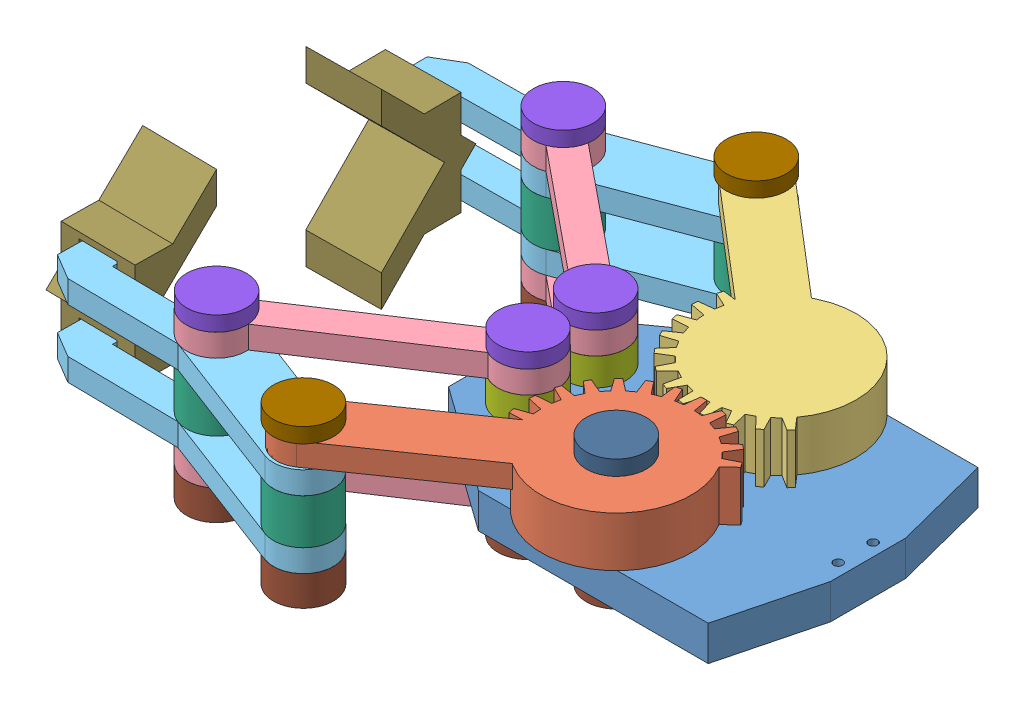
SolidWorks assembly 어셈블리4, configuration 기본. Lengths in mm.
Overall size (177.49 61.17 180).
35 component instances, 12 part files, 78 mates.
Components (placement in the parent):
- base(1)_final-1: base(1)_final [Default] at (138.3176 -17.9209 180) size (117.13 45.17 180)
- gear(2) _M_final-1: gear(2) _M_final [Default] at (28.6998 -14.4209 184.684) x (0.821002 0 -0.570925) z (0.570925 0 0.821002) size (68.4 10 32.98)
- gear_pulley_final-1: gear_pulley_final [Default] at (26.9685 18.9124 176.8375) x (0.760222 0 0.649664) z (0.649664 0 -0.760222) size (68.4 22 32.98)
- arm(4)_final-1: arm(4)_final [Default] at (-36.912 -2.5042 199.1511) x (0.834904 0 -0.550395) z (0.550395 0 0.834904) size (57 4.5 12)
- arm(4)_final-2: arm(4)_final [Default] at (-35.5671 12.4958 159.0173) x (-0.775131 0 -0.631801) z (-0.631801 0 0.775131) size (57 4.5 12)
- lever(4)_final-1: lever(4)_final [Default] at (-64.1108 -7.0042 202.4698) x (-0.934782 0 -0.355221) z (0.355221 0 -0.934782) size (66 4.5 19.65)
- lever(4)_final-2: lever(4)_final [Default] at (-61.4597 7.9958 153.8309) x (-0.936293 0 0.35122) z (0.35122 0 0.936293) size (66 4.5 19.65)
- ring_connect(4)_9mm_final-1: ring_connect(4)_9mm_final [기본] at (-55.6973 -10.7542 211.535) x (0.983529 0 0.180751) z (-0.180751 0 0.983529) size (12 9 12)
- ring_connect(4)_9mm_final-2: ring_connect(4)_9mm_final [기본] at (-53.0075 -10.7542 144.8017) size (12 9 12)
- ring_connect_6mm용(4)_5.5mm_final-1: ring_connect_6mm용(4)_5.5mm_final [기본] at (-18.1267 2.7458 173.2328) x (0.837169 0 0.546944) z (0.546944 0 -0.837169) size (12 5.5 12)
- ring_connect_6mm용(4)_5.5mm_final-2: ring_connect_6mm용(4)_5.5mm_final [기본] at (-18.1267 2.7458 186.7672) x (0.837169 0 0.546944) z (0.546944 0 -0.837169) size (12 5.5 12)
- lever(4)_final-3: lever(4)_final [Default] at (-64.1108 -20.5042 202.4698) x (-0.934782 0 -0.355221) z (0.355221 0 -0.934782) size (66 4.5 19.65)
- lever(4)_final-4: lever(4)_final [Default] at (-61.4597 -5.5042 153.8309) x (-0.936293 0 0.35122) z (0.35122 0 0.936293) size (66 4.5 19.65)
- ring_connect(4)_9mm_final-3: ring_connect(4)_9mm_final [기본] at (-27.6539 -10.7542 222.1916) x (0.987416 0 -0.158147) z (0.158147 0 0.987416) size (12 9 12)
- ring_connect(4)_9mm_final-4: ring_connect(4)_9mm_final [기본] at (-24.9187 -10.7542 134.2651) size (12 9 12)
- ring_connect_6mm용(4)_5.5mm_final-3: ring_connect_6mm용(4)_5.5mm_final [기본] at (-18.1267 -15.2542 186.7672) size (12 5.5 12)
- ring_connect_6mm용(4)_5.5mm_final-4: ring_connect_6mm용(4)_5.5mm_final [기본] at (-18.1267 -15.2542 173.2328) size (12 5.5 12)
- arm(4)_final-3: arm(4)_final [Default] at (-36.912 -25.0042 199.1511) x (0.834904 0 -0.550395) z (0.550395 0 0.834904) size (57 4.5 12)
- arm(4)_final-4: arm(4)_final [Default] at (-35.5671 -25.0042 159.0173) x (0.775131 0 0.631801) z (-0.631801 0 0.775131) size (57 4.5 12)
- link_5.5(4)(2)_30mm_final-1: link_5.5(4)(2)_30mm_final [Default] at (-55.6973 -51.2542 211.535) size (12 33 12)
- link_5.5(4)(2)_30mm_final-2: link_5.5(4)(2)_30mm_final [Default] at (-53.0075 -51.2542 144.8017) size (12 33 12)
- link2_5.5(2)_25.5mm_final-1: link2_5.5(2)_25.5mm_final [Default] at (-27.6539 -48.0042 222.1916) size (12 28.5 12)
- link2_5.5(2)_25.5mm_final-2: link2_5.5(2)_25.5mm_final [Default] at (-24.9187 -48.0042 134.2651) size (12 28.5 12)
- link_5.5(4)(2)_30mm_final-3: link_5.5(4)(2)_30mm_final [Default] at (-18.1267 -51.2542 186.7672) size (12 33 12)
- link_5.5(4)(2)_30mm_final-4: link_5.5(4)(2)_30mm_final [Default] at (-18.1267 -51.2542 173.2328) size (12 33 12)
- link3_5.5_gripper_gear_fianl-1: link3_5.5_gripper_gear_fianl [Default] at (9.2912 -36.0876 196.5) size (12 23 12)
- ring_5.5mm_final-3: ring_5.5mm_final [기본] at (-27.6539 -15.2542 222.1916) x (-0.837169 0 -0.546944) z (-0.546944 0 0.837169) size (12 6 12)
- ring_5.5mm_final-4: ring_5.5mm_final [기본] at (-18.1267 -19.7542 186.7672) x (-0.837169 0 -0.546944) z (-0.546944 0 0.837169) size (12 6 12)
- ring_5.5mm_final-5: ring_5.5mm_final [기본] at (-18.1267 -19.7542 173.2328) x (-0.837169 0 -0.546944) z (-0.546944 0 0.837169) size (12 6 12)
- ring_5.5mm_final-6: ring_5.5mm_final [기본] at (-55.6973 -19.7542 211.535) x (-0.837169 0 -0.546944) z (-0.546944 0 0.837169) size (12 6 12)
- ring_5.5mm_final-7: ring_5.5mm_final [기본] at (-53.0075 -19.7542 144.8017) x (-0.837169 0 -0.546944) z (-0.546944 0 0.837169) size (12 6 12)
- ring_5.5mm_final-8: ring_5.5mm_final [기본] at (9.2912 -9.7542 196.5) x (-0.837169 0 -0.546944) z (-0.546944 0 0.837169) size (12 6 12)
- ring_5.5mm_final-9: ring_5.5mm_final [기본] at (-24.9187 -15.2542 134.2651) x (-0.837169 0 -0.546944) z (-0.546944 0 0.837169) size (12 6 12)
- grip(2)_final-1: grip(2)_final [기본] at (-86.5672 -6.0442 204.573) x (0 1 0) z (0.014084 0 -0.999901) size (38.18 15 19.09)
- grip(2)_final-2: grip(2)_final [기본] at (-83.9068 -6.0442 151.6317) x (0 -1 0) z (0.009808 0 0.999952) size (38.18 15 19.09)
Mates (geometry in assembly coordinates):
- 일치1: coincident anti-aligned: plane of base(1)_final-1 through (43.1901 -2.7542 180) normal (0 1 0); plane of gear(2) _M_final-1 through (-27.6539 -2.7542 222.1916) normal (0 -1 0)
- 동심1: concentric aligned: cylinder of base(1)_final-1 through (9.2912 -2.7542 196.5) axis (0 1 0) radius 3; cylinder of gear(2) _M_final-1 through (9.2912 7.2458 196.5) axis (0 1 0) radius 3
- 일치2: coincident anti-aligned: plane of base(1)_final-1 through (43.1901 -2.7542 180) normal (0 1 0); plane of gear_pulley_final-1 through (-24.9187 -2.7542 134.2651) normal (0 -1 0)
- 동심2: concentric anti-aligned: cylinder of base(1)_final-1 through (9.2912 -2.7542 163.5) axis (0 -1 0) radius 6; cylinder of gear_pulley_final-1 through (9.2912 -14.7542 163.5) axis (0 1 0) radius 5.75
- 기어 메이트2: gear = 30 : 30 mm: cylinder of gear_pulley_final-1 through (9.2912 -2.7542 163.5) axis (0 1 0) radius 15; cylinder of gear(2) _M_final-1 through (9.2912 7.2458 196.5) axis (0 -1 0) radius 15
- 일치4: coincident aligned: plane of gear(2) _M_final-1 through (-27.6539 7.2458 222.1916) normal (0 1 0); plane of arm(4)_final-1 through (-55.6973 7.2458 211.535) normal (0 1 0)
- 동심5: concentric aligned: cylinder of base(1)_final-1 through (-18.1267 -2.7542 186.7672) axis (0 1 0) radius 3; cylinder of arm(4)_final-1 through (-18.1267 7.2458 186.7672) axis (0 1 0) radius 3
- 동심6: concentric anti-aligned: cylinder of base(1)_final-1 through (-18.1267 -2.7542 173.2328) axis (0 1 0) radius 3; cylinder of arm(4)_final-2 through (-18.1267 2.7458 173.2328) axis (0 -1 0) radius 3
- 일치6: coincident anti-aligned: plane of gear_pulley_final-1 through (9.2912 2.7458 163.5) normal (0 -1 0); plane of lever(4)_final-2 through (-53.0075 2.7458 144.8017) normal (0 1 0)
- 동심7: concentric aligned: cylinder of gear_pulley_final-1 through (-24.9187 -2.7542 134.2651) axis (0 -1 0) radius 3; cylinder of lever(4)_final-2 through (-24.9187 -1.7542 134.2651) axis (0 -1 0) radius 3
- 동심8: concentric aligned: cylinder of arm(4)_final-2 through (-53.0075 2.7458 144.8017) axis (0 -1 0) radius 3; cylinder of lever(4)_final-2 through (-53.0075 -1.7542 144.8017) axis (0 -1 0) radius 3
- 일치7: coincident aligned: plane of gear_pulley_final-1 through (-24.9187 7.2458 134.2651) normal (0 1 0); plane of arm(4)_final-2 through (-18.1267 7.2458 173.2328) normal (0 1 0)
- 일치8: coincident anti-aligned: plane of gear(2) _M_final-1 through (9.2912 2.7458 196.5) normal (0 -1 0); plane of lever(4)_final-1 through (-55.6973 2.7458 211.535) normal (0 1 0)
- 동심9: concentric aligned: cylinder of gear(2) _M_final-1 through (-27.6539 7.2458 222.1916) axis (0 1 0) radius 3; cylinder of lever(4)_final-1 through (-27.6539 2.7458 222.1916) axis (0 1 0) radius 3
- 일치9: coincident aligned: cylinder of arm(4)_final-1 through (-55.6973 7.2458 211.535) axis (0 1 0) radius 3; circle of lever(4)_final-1
- 일치11: coincident anti-aligned: plane of lever(4)_final-1 through (-55.6973 -1.7542 211.535) normal (0 -1 0); plane of ring_connect(4)_9mm_final-1 through (-55.6973 -1.7542 211.535) normal (0 1 0)
- 동심10: concentric anti-aligned: cylinder of lever(4)_final-1 through (-55.6973 2.7458 211.535) axis (0 1 0) radius 3; cylinder of ring_connect(4)_9mm_final-1 through (-55.6973 -1.7542 211.535) axis (0 -1 0) radius 3
- 일치12: coincident anti-aligned: plane of lever(4)_final-2 through (-53.0075 -1.7542 144.8017) normal (0 -1 0); plane of ring_connect(4)_9mm_final-2 through (-53.0075 -1.7542 144.8017) normal (0 1 0)
- 동심11: concentric aligned: cylinder of lever(4)_final-2 through (-53.0075 -1.7542 144.8017) axis (0 -1 0) radius 3; cylinder of ring_connect(4)_9mm_final-2 through (-53.0075 -1.7542 144.8017) axis (0 -1 0) radius 3
- 일치16: coincident anti-aligned: plane of base(1)_final-1 through (43.1901 -2.7542 180) normal (0 1 0); plane of ring_connect_6mm용(4)_5.5mm_final-2 through (-18.1267 -2.7542 186.7672) normal (0 -1 0)
- 동심14: concentric aligned: cylinder of arm(4)_final-1 through (-18.1267 7.2458 186.7672) axis (0 1 0) radius 3; cylinder of ring_connect_6mm용(4)_5.5mm_final-2 through (-18.1267 -2.7542 186.7672) axis (0 1 0) radius 3
- 일치17: coincident anti-aligned: plane of base(1)_final-1 through (43.1901 -2.7542 180) normal (0 1 0); plane of ring_connect_6mm용(4)_5.5mm_final-1 through (-18.1267 -2.7542 173.2328) normal (0 -1 0)
- 동심15: concentric aligned: cylinder of base(1)_final-1 through (-18.1267 -2.7542 173.2328) axis (0 1 0) radius 3; cylinder of ring_connect_6mm용(4)_5.5mm_final-1 through (-18.1267 -2.7542 173.2328) axis (0 1 0) radius 3
- 동심18: concentric anti-aligned: cylinder of ring_connect(4)_9mm_final-1 through (-55.6973 -1.7542 211.535) axis (0 -1 0) radius 3; cylinder of lever(4)_final-3 through (-55.6973 -10.7542 211.535) axis (0 1 0) radius 3
- 동심19: concentric aligned: cylinder of lever(4)_final-1 through (-27.6539 2.7458 222.1916) axis (0 1 0) radius 3; cylinder of lever(4)_final-3 through (-27.6539 -10.7542 222.1916) axis (0 1 0) radius 3
- 동심20: concentric anti-aligned: cylinder of lever(4)_final-1 through (-27.6539 2.7458 222.1916) axis (0 1 0) radius 3; cylinder of ring_connect(4)_9mm_final-3 through (-27.6539 -1.7542 222.1916) axis (0 -1 0) radius 3
- 일치21: coincident anti-aligned: plane of lever(4)_final-3 through (-55.6973 -10.7542 211.535) normal (0 1 0); plane of ring_connect(4)_9mm_final-3 through (-27.6539 -10.7542 222.1916) normal (0 -1 0)
- 동심22: concentric aligned: cylinder of ring_connect(4)_9mm_final-2 through (-53.0075 -1.7542 144.8017) axis (0 -1 0) radius 3; cylinder of lever(4)_final-4 through (-53.0075 -15.2542 144.8017) axis (0 -1 0) radius 3
- 일치22: coincident anti-aligned: plane of ring_connect(4)_9mm_final-2 through (-53.0075 -10.7542 144.8017) normal (0 -1 0); plane of lever(4)_final-4 through (-53.0075 -10.7542 144.8017) normal (0 1 0)
- 일치23: coincident anti-aligned: plane of lever(4)_final-4 through (-53.0075 -10.7542 144.8017) normal (0 1 0); plane of ring_connect(4)_9mm_final-4 through (-24.9187 -10.7542 134.2651) normal (0 -1 0)
- 동심24: concentric aligned: cylinder of gear_pulley_final-1 through (-24.9187 -2.7542 134.2651) axis (0 -1 0) radius 3; cylinder of ring_connect(4)_9mm_final-4 through (-24.9187 -1.7542 134.2651) axis (0 -1 0) radius 3
- 일치24: coincident anti-aligned: plane of base(1)_final-1 through (43.1901 -9.7542 180) normal (0 -1 0); plane of ring_connect_6mm용(4)_5.5mm_final-4 through (-18.1267 -9.7542 173.2328) normal (0 1 0)
- 일치25: coincident anti-aligned: plane of base(1)_final-1 through (43.1901 -9.7542 180) normal (0 -1 0); plane of ring_connect_6mm용(4)_5.5mm_final-3 through (-18.1267 -9.7542 186.7672) normal (0 1 0)
- 동심25: concentric anti-aligned: cylinder of base(1)_final-1 through (-18.1267 -2.7542 186.7672) axis (0 1 0) radius 3; cylinder of ring_connect_6mm용(4)_5.5mm_final-3 through (-18.1267 -9.7542 186.7672) axis (0 -1 0) radius 3
- 동심26: concentric anti-aligned: cylinder of base(1)_final-1 through (-18.1267 -2.7542 173.2328) axis (0 1 0) radius 3; cylinder of ring_connect_6mm용(4)_5.5mm_final-4 through (-18.1267 -9.7542 173.2328) axis (0 -1 0) radius 3
- 일치26: coincident anti-aligned: plane of lever(4)_final-3 through (-55.6973 -15.2542 211.535) normal (0 -1 0); plane of arm(4)_final-3 through (-55.6973 -15.2542 211.535) normal (0 1 0)
- 동심29: concentric aligned: cylinder of lever(4)_final-3 through (-55.6973 -10.7542 211.535) axis (0 1 0) radius 3; cylinder of arm(4)_final-3 through (-55.6973 -15.2542 211.535) axis (0 1 0) radius 3
- 동심30: concentric anti-aligned: cylinder of ring_connect_6mm용(4)_5.5mm_final-3 through (-18.1267 -9.7542 186.7672) axis (0 -1 0) radius 3; cylinder of arm(4)_final-3 through (-18.1267 -15.2542 186.7672) axis (0 1 0) radius 3
- 동심31: concentric anti-aligned: cylinder of ring_connect_6mm용(4)_5.5mm_final-4 through (-18.1267 -9.7542 173.2328) axis (0 -1 0) radius 3; cylinder of arm(4)_final-4 through (-18.1267 -15.2542 173.2328) axis (0 1 0) radius 3
- 일치27: coincident anti-aligned: plane of ring_connect_6mm용(4)_5.5mm_final-4 through (-18.1267 -15.2542 173.2328) normal (0 -1 0); plane of arm(4)_final-4 through (-53.0075 -15.2542 144.8017) normal (0 1 0)
- 동심32: concentric anti-aligned: cylinder of lever(4)_final-4 through (-53.0075 -15.2542 144.8017) axis (0 -1 0) radius 3; cylinder of arm(4)_final-4 through (-53.0075 -15.2542 144.8017) axis (0 1 0) radius 3
- 동심33: concentric anti-aligned: cylinder of arm(4)_final-1 through (-55.6973 7.2458 211.535) axis (0 1 0) radius 3; cylinder of link_5.5(4)(2)_30mm_final-1 through (-55.6973 15.731 211.535) axis (0 -1 0) radius 2.75
- 일치28: coincident anti-aligned: plane of arm(4)_final-1 through (-55.6973 7.2458 211.535) normal (0 1 0); plane of link_5.5(4)(2)_30mm_final-1 through (-55.6973 7.2458 211.535) normal (0 -1 0)
- 동심34: concentric aligned: cylinder of arm(4)_final-2 through (-53.0075 2.7458 144.8017) axis (0 -1 0) radius 3; cylinder of link_5.5(4)(2)_30mm_final-2 through (-53.0075 15.731 144.8017) axis (0 -1 0) radius 2.75
- 일치29: coincident anti-aligned: plane of arm(4)_final-2 through (-18.1267 7.2458 173.2328) normal (0 1 0); plane of link_5.5(4)(2)_30mm_final-2 through (-53.0075 7.2458 144.8017) normal (0 -1 0)
- 일치30: coincident anti-aligned: plane of gear(2) _M_final-1 through (-27.6539 7.2458 222.1916) normal (0 1 0); plane of link2_5.5(2)_25.5mm_final-1 through (-27.6539 7.2458 222.1916) normal (0 -1 0)
- 동심35: concentric anti-aligned: cylinder of lever(4)_final-3 through (-27.6539 -10.7542 222.1916) axis (0 1 0) radius 3; cylinder of link2_5.5(2)_25.5mm_final-1 through (-27.6539 15.731 222.1916) axis (0 -1 0) radius 2.75
- 일치33: coincident anti-aligned: plane of ring_connect(4)_9mm_final-1 through (-55.6973 -10.7542 211.535) normal (0 -1 0); plane of lever(4)_final-3 through (-55.6973 -10.7542 211.535) normal (0 1 0)
- 동심36: concentric aligned: cylinder of lever(4)_final-4 through (-24.9187 -15.2542 134.2651) axis (0 -1 0) radius 3; cylinder of ring_connect(4)_9mm_final-4 through (-24.9187 -1.7542 134.2651) axis (0 -1 0) radius 3
- 동심37: concentric aligned: cylinder of gear_pulley_final-1 through (-24.9187 -2.7542 134.2651) axis (0 -1 0) radius 3; cylinder of link2_5.5(2)_25.5mm_final-2 through (-24.9187 15.731 134.2651) axis (0 -1 0) radius 2.75
- 일치34: coincident anti-aligned: plane of gear_pulley_final-1 through (-24.9187 7.2458 134.2651) normal (0 1 0); plane of link2_5.5(2)_25.5mm_final-2 through (-24.9187 7.2458 134.2651) normal (0 -1 0)
- 동심38: concentric anti-aligned: cylinder of arm(4)_final-1 through (-18.1267 7.2458 186.7672) axis (0 1 0) radius 3; cylinder of link_5.5(4)(2)_30mm_final-3 through (-18.1267 15.731 186.7672) axis (0 -1 0) radius 2.75
- 일치35: coincident anti-aligned: plane of arm(4)_final-1 through (-55.6973 7.2458 211.535) normal (0 1 0); plane of link_5.5(4)(2)_30mm_final-3 through (-18.1267 7.2458 186.7672) normal (0 -1 0)
- 동심39: concentric aligned: cylinder of arm(4)_final-2 through (-18.1267 2.7458 173.2328) axis (0 -1 0) radius 3; cylinder of link_5.5(4)(2)_30mm_final-4 through (-18.1267 15.731 173.2328) axis (0 -1 0) radius 2.75
- 일치36: coincident anti-aligned: plane of arm(4)_final-2 through (-18.1267 7.2458 173.2328) normal (0 1 0); plane of link_5.5(4)(2)_30mm_final-4 through (-18.1267 7.2458 173.2328) normal (0 -1 0)
- 동심40: concentric anti-aligned: cylinder of gear(2) _M_final-1 through (9.2912 7.2458 196.5) axis (0 1 0) radius 3; cylinder of link3_5.5_gripper_gear_fianl-1 through (9.2912 15.731 196.5) axis (0 -1 0) radius 2.75
- 일치37: coincident anti-aligned: plane of gear(2) _M_final-1 through (-27.6539 7.2458 222.1916) normal (0 1 0); plane of link3_5.5_gripper_gear_fianl-1 through (9.2912 7.2458 196.5) normal (0 -1 0)
- 일치38: coincident anti-aligned: plane of arm(4)_final-3 through (-55.6973 -19.7542 211.535) normal (0 -1 0); plane of ring_5.5mm_final-6 through (-55.6973 -19.7542 211.535) normal (0 1 0)
- 일치40: coincident anti-aligned: plane of link_5.5(4)(2)_30mm_final-1 through (-55.6973 -22.7542 211.535) normal (0 -1 0); plane of ring_5.5mm_final-6 through (-55.6973 -22.7542 211.535) normal (0 1 0)
- 동심41: concentric anti-aligned: cylinder of link_5.5(4)(2)_30mm_final-1 through (-55.6973 15.731 211.535) axis (0 -1 0) radius 2.75; cylinder of ring_5.5mm_final-6 through (-55.6973 -22.7542 211.535) axis (0 1 0) radius 3
- 일치41: coincident anti-aligned: plane of arm(4)_final-4 through (-53.0075 -19.7542 144.8017) normal (0 -1 0); plane of ring_5.5mm_final-7 through (-53.0075 -19.7542 144.8017) normal (0 1 0)
- 동심42: concentric anti-aligned: cylinder of link_5.5(4)(2)_30mm_final-2 through (-53.0075 15.731 144.8017) axis (0 -1 0) radius 2.75; cylinder of ring_5.5mm_final-7 through (-53.0075 -22.7542 144.8017) axis (0 1 0) radius 3
- 일치42: coincident anti-aligned: plane of lever(4)_final-3 through (-55.6973 -15.2542 211.535) normal (0 -1 0); plane of ring_5.5mm_final-3 through (-27.6539 -15.2542 222.1916) normal (0 1 0)
- 동심43: concentric anti-aligned: cylinder of link2_5.5(2)_25.5mm_final-1 through (-27.6539 15.731 222.1916) axis (0 -1 0) radius 2.75; cylinder of ring_5.5mm_final-3 through (-27.6539 -18.2542 222.1916) axis (0 1 0) radius 3
- 일치43: coincident anti-aligned: plane of arm(4)_final-3 through (-55.6973 -19.7542 211.535) normal (0 -1 0); plane of ring_5.5mm_final-4 through (-18.1267 -19.7542 186.7672) normal (0 1 0)
- 동심44: concentric anti-aligned: cylinder of link_5.5(4)(2)_30mm_final-3 through (-18.1267 15.731 186.7672) axis (0 -1 0) radius 2.75; cylinder of ring_5.5mm_final-4 through (-18.1267 -22.7542 186.7672) axis (0 1 0) radius 3
- 일치45: coincident anti-aligned: plane of arm(4)_final-4 through (-53.0075 -19.7542 144.8017) normal (0 -1 0); plane of ring_5.5mm_final-5 through (-18.1267 -19.7542 173.2328) normal (0 1 0)
- 동심45: concentric anti-aligned: cylinder of link_5.5(4)(2)_30mm_final-4 through (-18.1267 15.731 173.2328) axis (0 -1 0) radius 2.75; cylinder of ring_5.5mm_final-5 through (-18.1267 -22.7542 173.2328) axis (0 1 0) radius 3
- 일치46: coincident anti-aligned: plane of lever(4)_final-4 through (-53.0075 -15.2542 144.8017) normal (0 -1 0); plane of ring_5.5mm_final-9 through (-24.9187 -15.2542 134.2651) normal (0 1 0)
- 동심46: concentric anti-aligned: cylinder of link2_5.5(2)_25.5mm_final-2 through (-24.9187 15.731 134.2651) axis (0 -1 0) radius 2.75; cylinder of ring_5.5mm_final-9 through (-24.9187 -18.2542 134.2651) axis (0 1 0) radius 3
- 일치47: coincident anti-aligned: plane of base(1)_final-1 through (43.1901 -9.7542 180) normal (0 -1 0); plane of ring_5.5mm_final-8 through (9.2912 -9.7542 196.5) normal (0 1 0)
- 동심47: concentric anti-aligned: cylinder of link3_5.5_gripper_gear_fianl-1 through (9.2912 15.731 196.5) axis (0 -1 0) radius 2.75; cylinder of ring_5.5mm_final-8 through (9.2912 -12.7542 196.5) axis (0 1 0) radius 3
- 일치48: coincident anti-aligned: plane of lever(4)_final-3 through (-55.6077 -10.7542 205.1738) normal (0.014084 0 -0.999901); plane of grip(2)_final-1 through (-89.0692 -6.0442 204.7025) normal (-0.014084 0 0.999901)
- 일치50: coincident anti-aligned: plane of lever(4)_final-3 through (-55.6973 -15.2542 211.535) normal (0 -1 0); plane of grip(2)_final-1 through (-77.7154 -15.2542 204.8624) normal (0 1 0)
- 일치51: coincident anti-aligned: plane of lever(4)_final-3 through (-77.805 -10.7542 211.2236) normal (0.999901 0 0.014084); plane of grip(2)_final-1 through (-77.7154 -10.5442 204.8624) normal (-0.999901 0 -0.014084)
- 일치52: coincident anti-aligned: plane of lever(4)_final-4 through (-52.9451 -15.2542 151.1633) normal (0.009808 0 0.999952); plane of grip(2)_final-2 through (-86.4083 -6.0442 151.4915) normal (-0.009808 0 -0.999952)
- 일치53: coincident anti-aligned: plane of lever(4)_final-4 through (-75.1163 -15.2542 145.0186) normal (0.999952 0 -0.009808); plane of grip(2)_final-2 through (-75.0539 -15.2542 151.3801) normal (-0.999952 0 0.009808)
- 일치54: coincident anti-aligned: plane of lever(4)_final-4 through (-53.0075 -15.2542 144.8017) normal (0 -1 0); plane of grip(2)_final-2 through (-75.0539 -15.2542 151.3801) normal (0 1 0)
